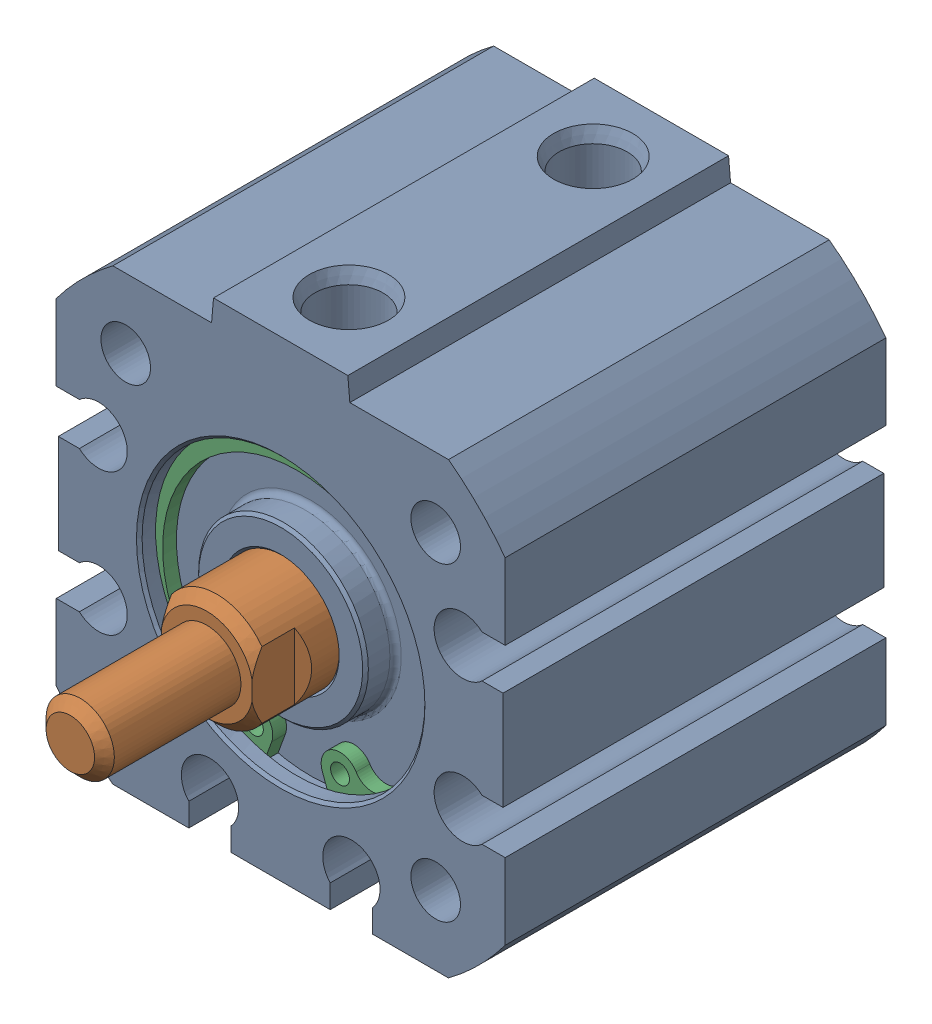
SolidWorks assembly 217-2778-001 Rev2_NCQ8A075-050M, configuration Default. Lengths in mm.
Overall size (31.75 33.34 41.8).
3 component instances, 3 part files, 0 mates.
Components (placement in the parent):
- 217-2778-NCQ8A075-050M_NCQ8 Tube_075A-1: 217-2778-NCQ8A075-050M_NCQ8 Tube_075A [Default] at origin size (31.75 33.34 26.92)
- 217-2778-NCQ8A075-050M_NCQ8 Rod_075M-1: 217-2778-NCQ8A075-050M_NCQ8 Rod_075M [Default] at (0 0 -6.927) x (-1 0 0) z (0 0 1) size (18.95 18.95 35.27)
- 217-2778-NCQ8A075-050M_Snap Ring_075-1: 217-2778-NCQ8A075-050M_Snap Ring_075 [Default] at (0 0 10.362) size (21 20.74 0.97)
